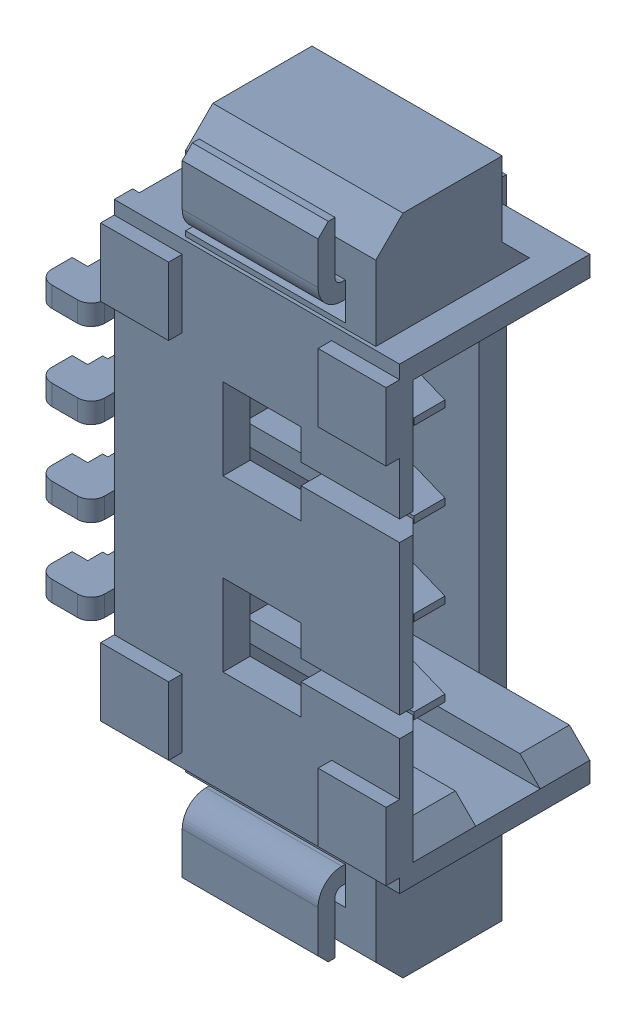
SolidWorks assembly P3, configuration Default. Lengths in mm.
Overall size (5.12 9.75 3.4).
2 component instances, 1 part files, 0 mates.
Components (placement in the parent):
- S-50271-004xx-xxx_RGB5527646-1: S-50271-004xx-xxx_RGB5527646 [Default] at (82.288 23.358 -3.3006) x (0 1 0) z (0 0 -1) size (9.75 5.12 3.4)
  - Open CASCADE STEP translator 6.8 1.86.1.1-1: Open CASCADE STEP translator 6.8 1.86.1.1 [Default] at origin size (9.75 5.12 3.4)
